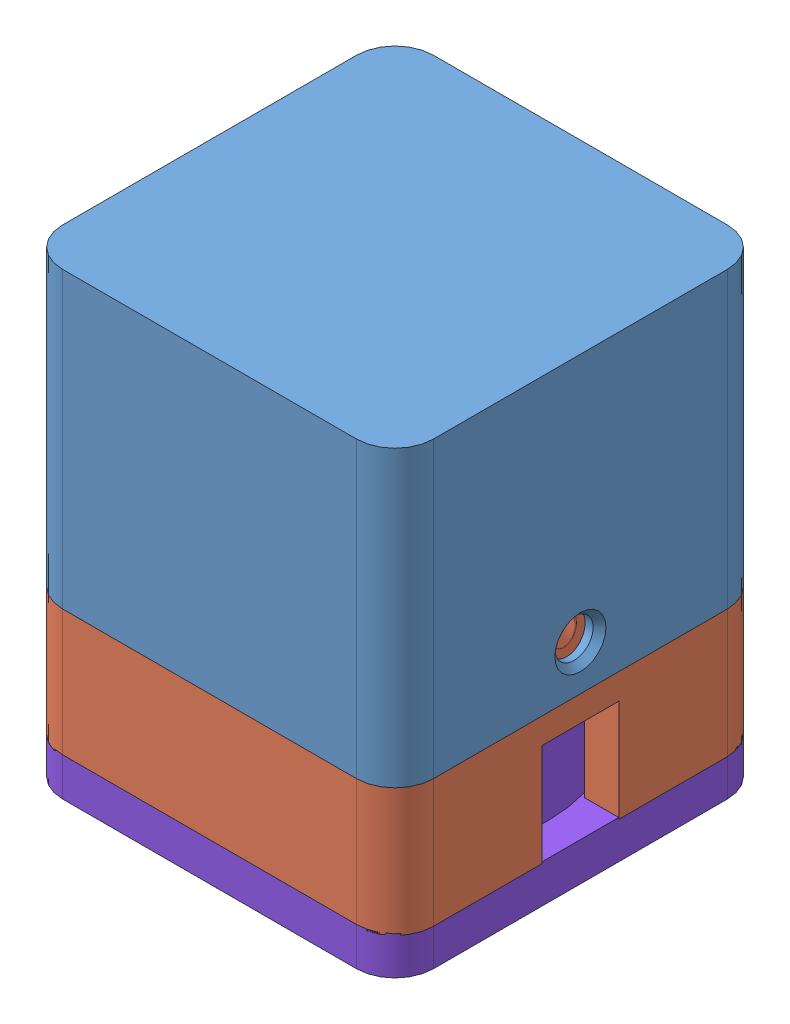
SolidWorks assembly mold_and_dome, configuration Default. Lengths in mm.
Overall size (29 35.87 29).
11 component instances, 8 part files, 6 mates.
Components (placement in the parent):
- tactile_dome_mold_outer-1: tactile_dome_mold_outer [Default] at origin size (29 23 29)
- tactile_dome-1: tactile_dome [Default] at (14.5 6.5 -14.5) size (29 29.2 29)
  - tactile_dome_outer-1: tactile_dome_outer [Default] at origin size (29 29.2 29)
    - dome_outer_rigidframe-1: dome_outer_rigidframe [Default] at origin size (29 16.65 29)
    - dome_outer_gel-1: dome_outer_gel [Default] at origin size (25.4 12.69 25.4)
    - dome_outer_markers-1: dome_outer_markers [Default] at origin size (22.95 7.51 22.91)
  - tactile_dome_inner-1: tactile_dome_inner [Default] at origin size (23.66 14 23.66)
    - dome_inner_rigidframe-1: dome_inner_rigidframe [Default] at origin size (23.66 3 23.66)
    - dome_inner_gel-1: dome_inner_gel [Default] at origin size (22 10.99 22)
    - dome_inner_markers-1: dome_inner_markers [Default] at origin size (19.94 6.6 19.91)
- tactile_dome_mold_inner-1: tactile_dome_mold_inner [Default] at (0 -12.874 0) size (29 29.85 29)
Mates (geometry in assembly coordinates):
- Coincident1: coordinate: point of tactile_dome_v2_mold_outer-1
- Concentric1: concentric anti-aligned: cylinder of tactile_dome_v2_mold_outer-1 through (14.5 6.75 -14.5) axis (0 -1 0) radius 13.45; cylinder of tactile_dome-1/tactile_dome_outer-1/dome_outer_rigidframe-1 through (14.5 4.5 -14.5) axis (0 1 0) radius 13.2
- Concentric2: concentric anti-aligned: cylinder of tactile_dome_v2_mold_outer-1 through (3 10 -26) axis (0 -1 0) radius 0.85; cylinder of tactile_dome-1/tactile_dome_outer-1/dome_outer_rigidframe-1 through (3 -10 -26) axis (0 1 0) radius 1.2
- Coincident2: coincident anti-aligned: plane of tactile_dome_v2_mold_outer-1 through (0 0 0) normal (0 -1 0); plane of tactile_dome-1/tactile_dome_outer-1/dome_outer_rigidframe-1 through (14.5 0 -14.5) normal (0 1 0)
- Concentric3: concentric anti-aligned: cylinder of tactile_dome-1/tactile_dome_outer-1/dome_outer_rigidframe-1 through (14.5 4.5 -14.5) axis (0 1 0) radius 12.2; cylinder of tactile_dome_v2_mold_inner-1 through (14.5 3.626 -14.5) axis (0 -1 0) radius 11.95
- Concentric4: concentric anti-aligned: cylinder of tactile_dome-1/tactile_dome_outer-1/dome_outer_rigidframe-1 through (26 -10 -26) axis (0 1 0) radius 1.2; cylinder of tactile_dome_v2_mold_inner-1 through (26 -9.874 -26) axis (0 -1 0) radius 1.2
